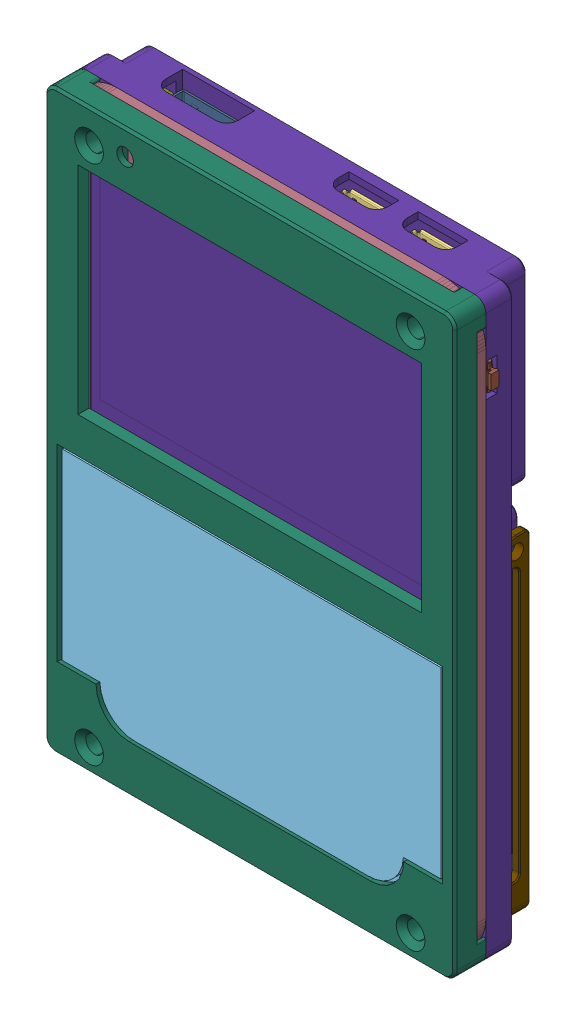
SolidWorks assembly beepy-v1, configuration 默认. Lengths in mm.
Overall size (74.67 104 15.57).
374 component instances, 56 part files, 23 mates.
Components (placement in the parent):
- Raspberry Pi Zero 2 W-1: Raspberry Pi Zero 2 W [默认] at (-86.2469 93.6162 0.7033) x (1 0 0) z (0 1 0) size (65.8 5.05 30.58)
  - PCB, Raspberry Pi Zero 2 W-1: PCB, Raspberry Pi Zero 2 W [默认] at origin size (65 1.6 30)
  - RP3A0-AU 2105 201221C, Raspberry Pi Zero 2 W-1: RP3A0-AU 2105 201221C, Raspberry Pi Zero 2 W [默认] at (-5.5 0.8 1) size (15 1 15)
  - MicroUSB Port, Raspberry Pi Zero 2 W-1: MicroUSB Port, Raspberry Pi Zero 2 W [默认] at (8.9 0.8 13) size (7.99 2.94 5.43)
  - SD Card Slot, Raspberry Pi Zero 2 W-1: SD Card Slot, Raspberry Pi Zero 2 W [默认] at (-25.5 0.8 -2) x (0 0 1) z (-1 0 0) size (11.95 1.45 11.4)
  - Wireless Module Cover, Raspberry Pi Zero 2 W-1: Wireless Module Cover, Raspberry Pi Zero 2 W [默认] at (11 0.8 1.5) size (12.6 1.6 12.6)
  - Crystal Resonator, Raspberry Pi Zero 2 W-1: Crystal Resonator, Raspberry Pi Zero 2 W [默认] at (-17.5 0.8 -1.5) size (2.2 0.6 3.2)
  - LED, Raspberry Pi Zero 2 W-1: LED, Raspberry Pi Zero 2 W [默认] at (27.5 0.8 7.8) size (1.2 0.4 0.8)
  - Diode, Schottky, Raspberry Pi Zero 2 W-1: Diode, Schottky, Raspberry Pi Zero 2 W [默认] at (-11 0.8 12) size (1.8 1 3.7)
  - 54548-2271, 22 Pin FPC Connector, Raspberry Pi Zero 2 W-1: 54548-2271, 22 Pin FPC Connector, Raspberry Pi Zero 2 W [默认] at (28.75 0.82 0) x (0 0 -1) z (1 0 0) size (16.2 1.2 5)
  - Mini HDMI Receptacle Port, Raspberry Pi Zero 2 W-1: Mini HDMI Receptacle Port, Raspberry Pi Zero 2 W [默认] at (-20.1 2.65 15) size (12.9 4.05 7.7)
  - PAM2306AYPKE, Switching Voltage Regulators Dual PWM Step-Down 40uA 1A_ 1.5MHz, Raspberry Pi Zero 2 W-1: PAM2306AYPKE, Switching Voltage Regulators Dual PWM Step-Down 40uA 1A_ 1.5MHz, Raspberry Pi Zero 2 W [默认] at (23 0.8 1) x (0 0 1) z (-1 0 0) size (3.4 1 3)
  - RT9081A-1BGQZA, Fixed LDO Voltage Regulator, 0.8V-5.5Vin, 140mV drop,_ 1.25Vout, 0.5Aout, Raspberry Pi Zero 2 W_default-1: RT9081A-1BGQZA, Fixed LDO Voltage Regulator, 0.8V-5.5Vin, 140mV drop,_ 1.25Vout, 0.5Aout, Raspberry Pi Zero 2 W_default [默认] at (14.8 0.8 -7.2) size (1.2 0.1 1.2)
  - RT8088AWSC, IC Reg Buck Prog 3A Sync 15WLCSP, Raspberry Pi Zero 2 W_d_efault-1: RT8088AWSC, IC Reg Buck Prog 3A Sync 15WLCSP, Raspberry Pi Zero 2 W_d_efault [默认] at (20 0.8 -3.6) size (1.36 0.4 2.16)
  - SMD Inductor, Configurable, Raspberry Pi Zero 2 W_L1-1: SMD Inductor, Configurable, Raspberry Pi Zero 2 W_L1 [默认] at (20.5 0.8 7.5) size (4 1.8 4)
  - SMD Inductor, Configurable, Raspberry Pi Zero 2 W_L2-1: SMD Inductor, Configurable, Raspberry Pi Zero 2 W_L2 [默认] at (24.5 0.8 -2) size (2.5 1.2 2)
  - SMD Capacitor, Configurable, Raspberry Pi Zero 2 W_C1-1: SMD Capacitor, Configurable, Raspberry Pi Zero 2 W_C1 [默认] at (24.9 0.8 7.7) size (1.2 0.45 2)
  - MicroUSB Port, Raspberry Pi Zero 2 W-2: MicroUSB Port, Raspberry Pi Zero 2 W [默认] at (21.5 0.8 13) size (7.99 2.94 5.43)
  - SMD Capacitor, Configurable, Raspberry Pi Zero 2 W_C3-1: SMD Capacitor, Configurable, Raspberry Pi Zero 2 W_C3 [默认] at (20.5 0.8 3) size (0.85 0.45 1.55)
  - SMD Capacitor, Configurable, Raspberry Pi Zero 2 W_C3-2: SMD Capacitor, Configurable, Raspberry Pi Zero 2 W_C3 [默认] at (18.7 0.8 3) size (0.85 0.45 1.55)
  - SMD Capacitor, Configurable, Raspberry Pi Zero 2 W_C1-2: SMD Capacitor, Configurable, Raspberry Pi Zero 2 W_C1 [默认] at (27.3 0.8 2.2) size (1.2 0.45 2)
  - SMD Capacitor, Configurable, Raspberry Pi Zero 2 W_C3-3: SMD Capacitor, Configurable, Raspberry Pi Zero 2 W_C3 [默认] at (25.7 0.8 2.2) size (0.85 0.45 1.55)
  - SMD Capacitor, Configurable, Raspberry Pi Zero 2 W_C1-3: SMD Capacitor, Configurable, Raspberry Pi Zero 2 W_C1 [默认] at (22.8 0.8 -5.1) x (0 0 -1) z (1 0 0) size (1.2 0.45 2)
  - SMD Capacitor, Configurable, Raspberry Pi Zero 2 W_C3-4: SMD Capacitor, Configurable, Raspberry Pi Zero 2 W_C3 [默认] at (20 0.8 -6.4) x (0 0 -1) z (1 0 0) size (0.85 0.45 1.55)
  - SMD Capacitor, Configurable, Raspberry Pi Zero 2 W_C3-5: SMD Capacitor, Configurable, Raspberry Pi Zero 2 W_C3 [默认] at (15.8 0.8 -6.1) x (0 0 -1) z (1 0 0) size (0.85 0.45 1.55)
  - SMD Capacitor, Configurable, Raspberry Pi Zero 2 W_C3-6: SMD Capacitor, Configurable, Raspberry Pi Zero 2 W_C3 [默认] at (13 0.8 -6.1) x (0 0 -1) z (1 0 0) size (0.85 0.45 1.55)
  - SMD Capacitor, Configurable, Raspberry Pi Zero 2 W_C3-7: SMD Capacitor, Configurable, Raspberry Pi Zero 2 W_C3 [默认] at (14.8 0.8 12.5) size (0.85 0.45 1.55)
  - SMD Capacitor, Configurable, Raspberry Pi Zero 2 W_C2-1: SMD Capacitor, Configurable, Raspberry Pi Zero 2 W_C2 [默认] at (-9.5 0.8 10.4) size (0.3 0.25 0.6)
  - SMD Capacitor, Configurable, Raspberry Pi Zero 2 W_C10-1: SMD Capacitor, Configurable, Raspberry Pi Zero 2 W_C10 [默认] at (-31.4 0.8 6) size (0.5 0.35 1)
  - SMD Capacitor, Configurable, Raspberry Pi Zero 2 W_C10-2: SMD Capacitor, Configurable, Raspberry Pi Zero 2 W_C10 [默认] at (-6.1 0.8 13.7) x (0 0 -1) z (1 0 0) size (0.5 0.35 1)
  - SMD Capacitor, Configurable, Raspberry Pi Zero 2 W_C10-3: SMD Capacitor, Configurable, Raspberry Pi Zero 2 W_C10 [默认] at (-2.9 0.8 13.7) x (0 0 -1) z (1 0 0) size (0.5 0.35 1)
  - SMD Capacitor, Configurable, Raspberry Pi Zero 2 W_C10-4: SMD Capacitor, Configurable, Raspberry Pi Zero 2 W_C10 [默认] at (-6.1 0.8 11.9) x (0 0 -1) z (1 0 0) size (0.5 0.35 1)
  - SMD Capacitor, Configurable, Raspberry Pi Zero 2 W_C10-5: SMD Capacitor, Configurable, Raspberry Pi Zero 2 W_C10 [默认] at (-2.9 0.8 11.9) x (0 0 -1) z (1 0 0) size (0.5 0.35 1)
  - SMD Capacitor, Configurable, Raspberry Pi Zero 2 W_C10-6: SMD Capacitor, Configurable, Raspberry Pi Zero 2 W_C10 [默认] at (-4.6 0.8 9.5) x (0 0 -1) z (1 0 0) size (0.5 0.35 1)
  - SMD Capacitor, Configurable, Raspberry Pi Zero 2 W_C10-7: SMD Capacitor, Configurable, Raspberry Pi Zero 2 W_C10 [默认] at (-7.3 0.8 8.9) x (0 0 -1) z (1 0 0) size (0.5 0.35 1)
  - SMD Capacitor, Configurable, Raspberry Pi Zero 2 W_C2-2: SMD Capacitor, Configurable, Raspberry Pi Zero 2 W_C2 [默认] at (-4.6 0.8 8.8) x (0 0 -1) z (1 0 0) size (0.3 0.25 0.6)
  - SMD Capacitor, Configurable, Raspberry Pi Zero 2 W_C10-8: SMD Capacitor, Configurable, Raspberry Pi Zero 2 W_C10 [默认] at (2.9 0.8 -1.5) x (-1 0 0) z (0 0 -1) size (0.5 0.35 1)
  - SMD Capacitor, Configurable, Raspberry Pi Zero 2 W_C10-9: SMD Capacitor, Configurable, Raspberry Pi Zero 2 W_C10 [默认] at (3.1 0.8 0.3) x (0 0 -1) z (1 0 0) size (0.5 0.35 1)
  - SMD Capacitor, Configurable, Raspberry Pi Zero 2 W_C2-3: SMD Capacitor, Configurable, Raspberry Pi Zero 2 W_C2 [默认] at (-2.4 0.8 8.8) x (0 0 -1) z (1 0 0) size (0.3 0.25 0.6)
  - SMD Capacitor, Configurable, Raspberry Pi Zero 2 W_C2-4: SMD Capacitor, Configurable, Raspberry Pi Zero 2 W_C2 [默认] at (-9.7 0.8 8.8) x (0 0 -1) z (1 0 0) size (0.3 0.25 0.6)
  - SMD Capacitor, Configurable, Raspberry Pi Zero 2 W_C2-5: SMD Capacitor, Configurable, Raspberry Pi Zero 2 W_C2 [默认] at (-8.5 0.8 9.2) x (-1 0 0) z (0 0 -1) size (0.3 0.25 0.6)
  - SMD Capacitor, Configurable, Raspberry Pi Zero 2 W_C2-6: SMD Capacitor, Configurable, Raspberry Pi Zero 2 W_C2 [默认] at (3.1 0.8 2.2) x (-1 0 0) z (0 0 -1) size (0.3 0.25 0.6)
  - SMD Capacitor, Configurable, Raspberry Pi Zero 2 W_C2-7: SMD Capacitor, Configurable, Raspberry Pi Zero 2 W_C2 [默认] at (3 0.8 3.7) x (-1 0 0) z (0 0 -1) size (0.3 0.25 0.6)
  - SMD Capacitor, Configurable, Raspberry Pi Zero 2 W_C2-8: SMD Capacitor, Configurable, Raspberry Pi Zero 2 W_C2 [默认] at (3 0.8 5.5) x (-1 0 0) z (0 0 -1) size (0.3 0.25 0.6)
  - SMD Capacitor, Configurable, Raspberry Pi Zero 2 W_C10-10: SMD Capacitor, Configurable, Raspberry Pi Zero 2 W_C10 [默认] at (-27.8 0.8 7.8) x (0 0 -1) z (1 0 0) size (0.5 0.35 1)
  - SMD Capacitor, Configurable, Raspberry Pi Zero 2 W_C2-9: SMD Capacitor, Configurable, Raspberry Pi Zero 2 W_C2 [默认] at (-12.7 0.8 13.7) x (0 0 -1) z (1 0 0) size (0.3 0.25 0.6)
  - SMD Capacitor, Configurable, Raspberry Pi Zero 2 W_C10-11: SMD Capacitor, Configurable, Raspberry Pi Zero 2 W_C10 [默认] at (-17.7 0.8 -3.8) x (0 0 -1) z (1 0 0) size (0.5 0.35 1)
  - SMD Capacitor, Configurable, Raspberry Pi Zero 2 W_C10-12: SMD Capacitor, Configurable, Raspberry Pi Zero 2 W_C10 [默认] at (-17.5 0.8 1) x (0 0 -1) z (1 0 0) size (0.5 0.35 1)
  - SMD Capacitor, Configurable, Raspberry Pi Zero 2 W_C2-10: SMD Capacitor, Configurable, Raspberry Pi Zero 2 W_C2 [默认] at (-7.7 0.8 -7.4) x (0 0 -1) z (1 0 0) size (0.3 0.25 0.6)
  - SMD Capacitor, Configurable, Raspberry Pi Zero 2 W_C2-11: SMD Capacitor, Configurable, Raspberry Pi Zero 2 W_C2 [默认] at (-5.4 0.8 -7.5) x (-1 0 0) z (0 0 -1) size (0.3 0.25 0.6)
  - SMD Capacitor, Configurable, Raspberry Pi Zero 2 W_C2-12: SMD Capacitor, Configurable, Raspberry Pi Zero 2 W_C2 [默认] at (-0.15 0.8 9) x (-1 0 0) z (0 0 -1) size (0.3 0.25 0.6)
  - SMD Capacitor, Configurable, Raspberry Pi Zero 2 W_C2-13: SMD Capacitor, Configurable, Raspberry Pi Zero 2 W_C2 [默认] at (-1.3 0.8 8.8) x (0 0 -1) z (1 0 0) size (0.3 0.25 0.6)
  - SMD Capacitor, Configurable, Raspberry Pi Zero 2 W_C10-13: SMD Capacitor, Configurable, Raspberry Pi Zero 2 W_C10 [默认] at (-15 0.8 6.4) x (0 0 -1) z (1 0 0) size (0.5 0.35 1)
  - SMD Capacitor, Configurable, Raspberry Pi Zero 2 W_C2-14: SMD Capacitor, Configurable, Raspberry Pi Zero 2 W_C2 [默认] at (-14.2 0.8 -2.1) x (0 0 -1) z (1 0 0) size (0.3 0.25 0.6)
  - SMD Capacitor, Configurable, Raspberry Pi Zero 2 W_C10-14: SMD Capacitor, Configurable, Raspberry Pi Zero 2 W_C10 [默认] at (-15 0.8 -1) size (0.5 0.35 1)
  - SMD Capacitor, Configurable, Raspberry Pi Zero 2 W_C10-15: SMD Capacitor, Configurable, Raspberry Pi Zero 2 W_C10 [默认] at (-14.9 0.8 1.1) size (0.5 0.35 1)
  - SMD Capacitor, Configurable, Raspberry Pi Zero 2 W_C2-15: SMD Capacitor, Configurable, Raspberry Pi Zero 2 W_C2 [默认] at (-14.3 0.8 -7.2) x (0 0 -1) z (1 0 0) size (0.3 0.25 0.6)
  - SMD Capacitor, Configurable, Raspberry Pi Zero 2 W_C2-16: SMD Capacitor, Configurable, Raspberry Pi Zero 2 W_C2 [默认] at (-14.1 0.8 -6) x (0 0 -1) z (1 0 0) size (0.3 0.25 0.6)
  - SMD Capacitor, Configurable, Raspberry Pi Zero 2 W_C2-17: SMD Capacitor, Configurable, Raspberry Pi Zero 2 W_C2 [默认] at (-13.3 0.8 1.7) size (0.3 0.25 0.6)
  - SMD Capacitor, Configurable, Raspberry Pi Zero 2 W_C2-18: SMD Capacitor, Configurable, Raspberry Pi Zero 2 W_C2 [默认] at (-13.3 0.8 -0.9) size (0.3 0.25 0.6)
  - SMD Capacitor, Configurable, Raspberry Pi Zero 2 W_C2-19: SMD Capacitor, Configurable, Raspberry Pi Zero 2 W_C2 [默认] at (-14.2 0.8 -2.7) x (0 0 -1) z (1 0 0) size (0.3 0.25 0.6)
  - SMD Capacitor, Configurable, Raspberry Pi Zero 2 W_C2-20: SMD Capacitor, Configurable, Raspberry Pi Zero 2 W_C2 [默认] at (-14.2 0.8 -3.3) x (0 0 -1) z (1 0 0) size (0.3 0.25 0.6)
  - SMD Capacitor, Configurable, Raspberry Pi Zero 2 W_C2-21: SMD Capacitor, Configurable, Raspberry Pi Zero 2 W_C2 [默认] at (-14.2 0.8 -3.9) x (0 0 -1) z (1 0 0) size (0.3 0.25 0.6)
  - SMD Capacitor, Configurable, Raspberry Pi Zero 2 W_C2-22: SMD Capacitor, Configurable, Raspberry Pi Zero 2 W_C2 [默认] at (-14.1 0.8 3.7) x (0 0 -1) z (1 0 0) size (0.3 0.25 0.6)
  - SMD Capacitor, Configurable, Raspberry Pi Zero 2 W_C2-23: SMD Capacitor, Configurable, Raspberry Pi Zero 2 W_C2 [默认] at (-15 0.8 3) size (0.3 0.25 0.6)
  - SMD Capacitor, Configurable, Raspberry Pi Zero 2 W_C2-24: SMD Capacitor, Configurable, Raspberry Pi Zero 2 W_C2 [默认] at (-15.8 0.8 3) size (0.3 0.25 0.6)
  - SMD Capacitor, Configurable, Raspberry Pi Zero 2 W_C2-25: SMD Capacitor, Configurable, Raspberry Pi Zero 2 W_C2 [默认] at (25.8 0.8 -5.6) x (0 0 -1) z (1 0 0) size (0.3 0.25 0.6)
  - SMD Capacitor, Configurable, Raspberry Pi Zero 2 W_C2-26: SMD Capacitor, Configurable, Raspberry Pi Zero 2 W_C2 [默认] at (25.1 0.8 -6.5) size (0.3 0.25 0.6)
  - SMD Capacitor, Configurable, Raspberry Pi Zero 2 W_C2-27: SMD Capacitor, Configurable, Raspberry Pi Zero 2 W_C2 [默认] at (25.3 0.8 4.9) x (0 0 -1) z (1 0 0) size (0.3 0.25 0.6)
  - SMD Capacitor, Configurable, Raspberry Pi Zero 2 W_C2-28: SMD Capacitor, Configurable, Raspberry Pi Zero 2 W_C2 [默认] at (18.7 0.8 -3) size (0.3 0.25 0.6)
  - SMD Capacitor, Configurable, Raspberry Pi Zero 2 W_C2-29: SMD Capacitor, Configurable, Raspberry Pi Zero 2 W_C2 [默认] at (6.9269 0.8 8.9) x (0 0 -1) z (1 0 0) size (0.3 0.25 0.6)
  - SMD Capacitor, Configurable, Raspberry Pi Zero 2 W_C2-30: SMD Capacitor, Configurable, Raspberry Pi Zero 2 W_C2 [默认] at (3.5 0.8 -1.5) x (-1 0 0) z (0 0 -1) size (0.3 0.25 0.6)
  - SMD Resistor, Configurable, Raspberry Pi Zero 2 W_R1-1: SMD Resistor, Configurable, Raspberry Pi Zero 2 W_R1 [默认] at (-18.4 0.8 -8.2) size (0.5 0.35 1)
  - SMD Resistor, Configurable, Raspberry Pi Zero 2 W_R1-2: SMD Resistor, Configurable, Raspberry Pi Zero 2 W_R1 [默认] at (-17.1 0.8 -8.2) size (0.5 0.35 1)
  - SMD Resistor, Configurable, Raspberry Pi Zero 2 W_R1-3: SMD Resistor, Configurable, Raspberry Pi Zero 2 W_R1 [默认] at (23.9 0.8 -8) size (0.5 0.35 1)
  - SMD Resistor, Configurable, Raspberry Pi Zero 2 W_R12-1: SMD Resistor, Configurable, Raspberry Pi Zero 2 W_R12 [默认] at (24.9 0.8 -8) size (0.3 0.23 0.6)
  - SMD Resistor, Configurable, Raspberry Pi Zero 2 W_R1-4: SMD Resistor, Configurable, Raspberry Pi Zero 2 W_R1 [默认] at (-10.8 0.8 -7.3) x (0 0 1) z (-1 0 0) size (0.5 0.35 1)
  - SMD Resistor, Configurable, Raspberry Pi Zero 2 W_R1-5: SMD Resistor, Configurable, Raspberry Pi Zero 2 W_R1 [默认] at (-14.3 0.8 -4.7) x (0 0 1) z (-1 0 0) size (0.5 0.35 1)
  - SMD Resistor, Configurable, Raspberry Pi Zero 2 W_R1-6: SMD Resistor, Configurable, Raspberry Pi Zero 2 W_R1 [默认] at (-13.3 0.8 -7.3) x (0 0 1) z (-1 0 0) size (0.5 0.35 1)
  - SMD Resistor, Configurable, Raspberry Pi Zero 2 W_R1-7: SMD Resistor, Configurable, Raspberry Pi Zero 2 W_R1 [默认] at (-17.7 0.8 -5.8) x (0 0 1) z (-1 0 0) size (0.5 0.35 1)
  - SMD Resistor, Configurable, Raspberry Pi Zero 2 W_R1-8: SMD Resistor, Configurable, Raspberry Pi Zero 2 W_R1 [默认] at (-17.7 0.8 -4.8) x (0 0 1) z (-1 0 0) size (0.5 0.35 1)
  - SMD Resistor, Configurable, Raspberry Pi Zero 2 W_R1-9: SMD Resistor, Configurable, Raspberry Pi Zero 2 W_R1 [默认] at (-27.7 0.8 4.8) x (0 0 1) z (-1 0 0) size (0.5 0.35 1)
  - SMD Resistor, Configurable, Raspberry Pi Zero 2 W_R1-10: SMD Resistor, Configurable, Raspberry Pi Zero 2 W_R1 [默认] at (-15 0.8 5.4) x (0 0 1) z (-1 0 0) size (0.5 0.35 1)
  - SMD Resistor, Configurable, Raspberry Pi Zero 2 W_R1-11: SMD Resistor, Configurable, Raspberry Pi Zero 2 W_R1 [默认] at (-6.7 0.8 9.6958) x (0 0 1) z (-1 0 0) size (0.5 0.35 1)
  - SMD Resistor, Configurable, Raspberry Pi Zero 2 W_R1-12: SMD Resistor, Configurable, Raspberry Pi Zero 2 W_R1 [默认] at (-11.7 0.8 8.9) x (0 0 1) z (-1 0 0) size (0.5 0.35 1)
  - SMD Resistor, Configurable, Raspberry Pi Zero 2 W_R1-13: SMD Resistor, Configurable, Raspberry Pi Zero 2 W_R1 [默认] at (24.8 0.8 5.7) x (0 0 1) z (-1 0 0) size (0.5 0.35 1)
  - SMD Resistor, Configurable, Raspberry Pi Zero 2 W_R1-14: SMD Resistor, Configurable, Raspberry Pi Zero 2 W_R1 [默认] at (27.2 0.8 4.3) x (0 0 1) z (-1 0 0) size (0.5 0.35 1)
  - SMD Resistor, Configurable, Raspberry Pi Zero 2 W_R1-15: SMD Resistor, Configurable, Raspberry Pi Zero 2 W_R1 [默认] at (27.2 0.8 5.3) x (0 0 1) z (-1 0 0) size (0.5 0.35 1)
  - SMD Resistor, Configurable, Raspberry Pi Zero 2 W_R1-16: SMD Resistor, Configurable, Raspberry Pi Zero 2 W_R1 [默认] at (27.2 0.8 6.4) x (0 0 1) z (-1 0 0) size (0.5 0.35 1)
  - SMD Resistor, Configurable, Raspberry Pi Zero 2 W_R1-17: SMD Resistor, Configurable, Raspberry Pi Zero 2 W_R1 [默认] at (26.5 0.8 -6.5) x (0 0 1) z (-1 0 0) size (0.5 0.35 1)
  - SMD Resistor, Configurable, Raspberry Pi Zero 2 W_R1-18: SMD Resistor, Configurable, Raspberry Pi Zero 2 W_R1 [默认] at (26.5 0.8 -7.4) x (0 0 1) z (-1 0 0) size (0.5 0.35 1)
  - SMD Resistor, Configurable, Raspberry Pi Zero 2 W_R1-19: SMD Resistor, Configurable, Raspberry Pi Zero 2 W_R1 [默认] at (26.5 0.8 -8.6) x (0 0 1) z (-1 0 0) size (0.5 0.35 1)
  - SMD Resistor, Configurable, Raspberry Pi Zero 2 W_R1-20: SMD Resistor, Configurable, Raspberry Pi Zero 2 W_R1 [默认] at (3.5 0.8 -6.6) x (0.707107 0 0.707107) z (-0.707107 0 0.707107) size (0.5 0.35 1)
  - SMD Capacitor, Configurable, Raspberry Pi Zero 2 W_C2-31: SMD Capacitor, Configurable, Raspberry Pi Zero 2 W_C2 [默认] at (14.6 0.8 -8.3) x (0 0 -1) z (1 0 0) size (0.3 0.25 0.6)
- beeperv2-1: beeperv2 [默认] at (-49.2569 6.9162 4.5433) size (74.67 104 10.1)
  - RGB LED SMD 2121 v1-1: RGB LED SMD 2121 v1 [默认] at (-59.47 99.29 1.62) size (2.1 2.1 1)
    - COMPOUND-1: COMPOUND [默认] at origin size (2.1 2.1 1)
  - R_0603_1608Metric-1: R_0603_1608Metric [默认] at (-46.22 67.4075 -0.05) x (-1 0 0) z (0 0 -1) size (1.6 0.8 0.45)
    - SOLID-1: SOLID [默认] at origin size (1.6 0.8 0.45)
  - s7141-45-1: s7141-45 [默认] at (-20.4916 74.98 -0.05) x (1 0 0) z (0 1 0) size (2.3 2.57 4.6)
    - COMPOUND (1)-1: COMPOUND (1) [默认] at origin size (2.3 2.57 4.6)
  - s7141-45-2: s7141-45 [默认] at (-28.1032 75.42 -0.05) x (-1 0 0) z (0 -1 0) size (2.3 2.57 4.6)
    - COMPOUND (1)-1: COMPOUND (1) [默认] at origin size (2.3 2.57 4.6)
  - s7141-45-3: s7141-45 [默认] at (-25.5726 74.98 -0.05) x (1 0 0) z (0 1 0) size (2.3 2.57 4.6)
    - COMPOUND (1)-1: COMPOUND (1) [默认] at origin size (2.3 2.57 4.6)
  - SSOP-8_5.25x5.24mm_P1.27mm-1: SSOP-8_5.25x5.24mm_P1.27mm [默认] at (-21.02 19.19 -0.05) x (1 0 0) z (0 0 -1) size (8.22 5.24 1.6)
    - SOLID (1)-1: SOLID (1) [默认] at origin size (8.22 5.24 1.6)
  - s7141-45-4: s7141-45 [默认] at (-53.5184 74.98 -0.05) x (1 0 0) z (0 1 0) size (2.3 2.57 4.6)
    - COMPOUND (1)-1: COMPOUND (1) [默认] at origin size (2.3 2.57 4.6)
  - R_0603_1608Metric-2: R_0603_1608Metric [默认] at (-15.62 33.785 -0.05) x (0 1 0) z (0 0 -1) size (1.6 0.8 0.45)
    - SOLID-1: SOLID [默认] at origin size (1.6 0.8 0.45)
  - SSOP-16_4.4x5.2mm_P0.65mm-1: SSOP-16_4.4x5.2mm_P0.65mm [默认] at (-56.8325 11.275 -0.05) x (-1 0 0) z (0 0 -1) size (6.5 5.2 1.4)
    - SOLID (2)-1: SOLID (2) [默认] at origin size (6.5 5.2 1.4)
  - SOT-23-1: SOT-23 [默认] at (-21.45 37.19 -0.05) x (0 -1 0) z (0 0 -1) size (2.5 3 1.2)
    - SOLID (3)-1: SOLID (3) [默认] at origin size (2.5 3 1.2)
  - SOT-23-5-1: SOT-23-5 [默认] at (-18.37 44.26 -0.05) x (0 1 0) z (0 0 -1) size (2.8 2.9 1.55)
    - SOLID (4)-1: SOLID (4) [默认] at origin size (2.8 2.9 1.55)
  - EVQPU-LC-02K-1: EVQPU-LC-02K [默认] at (-2.08 91.37 -0.05) x (0 -1 0) z (1 0 0) size (6.4 2.15 4.54)
    - SOLID (5)-1: SOLID (5) [默认] at origin size (6.4 2.15 4.54)
  - R_0603_1608Metric-3: R_0603_1608Metric [默认] at (-18.25 54.395 -0.05) x (0 1 0) z (0 0 -1) size (1.6 0.8 0.45)
    - SOLID-1: SOLID [默认] at origin size (1.6 0.8 0.45)
  - SOT-23-2: SOT-23 [默认] at (-10.48 51 -0.05) x (0 -1 0) z (0 0 -1) size (2.5 3 1.2)
    - SOLID (3)-1: SOLID (3) [默认] at origin size (2.5 3 1.2)
  - s7141-45-5: s7141-45 [默认] at (-38.2653 75.42 -0.05) x (-1 0 0) z (0 -1 0) size (2.3 2.57 4.6)
    - COMPOUND (1)-1: COMPOUND (1) [默认] at origin size (2.3 2.57 4.6)
  - SOT-23-5-2: SOT-23-5 [默认] at (-21.77 44.26 -0.05) x (0 1 0) z (0 0 -1) size (2.8 2.9 1.55)
    - SOLID (4)-1: SOLID (4) [默认] at origin size (2.8 2.9 1.55)
  - s7141-45-6: s7141-45 [默认] at (-15.4105 74.98 -0.05) x (1 0 0) z (0 1 0) size (2.3 2.57 4.6)
    - COMPOUND (1)-1: COMPOUND (1) [默认] at origin size (2.3 2.57 4.6)
  - s7141-45-7: s7141-45 [默认] at (-17.9411 75.42 -0.05) x (-1 0 0) z (0 -1 0) size (2.3 2.57 4.6)
    - COMPOUND (1)-1: COMPOUND (1) [默认] at origin size (2.3 2.57 4.6)
  - C_0603_1608Metric-1: C_0603_1608Metric [默认] at (-14.3 20.58 -0.05) x (0 -1 0) z (0 0 -1) size (1.6 0.8 0.8)
    - SOLID (6)-1: SOLID (6) [默认] at origin size (1.6 0.8 0.8)
  - C_1206_3216Metric-1: C_1206_3216Metric [默认] at (-63.04 13.75 -0.05) x (-1 0 0) z (0 0 -1) size (3.2 1.6 1.6)
    - SOLID (7)-1: SOLID (7) [默认] at origin size (3.2 1.6 1.6)
  - C_0603_1608Metric-2: C_0603_1608Metric [默认] at (-7.93 23.79 -0.05) x (1 0 0) z (0 0 -1) size (1.6 0.8 0.8)
    - SOLID (6)-1: SOLID (6) [默认] at origin size (1.6 0.8 0.8)
  - SOT-23-3: SOT-23 [默认] at (-17.28 50.995 -0.05) x (0 -1 0) z (0 0 -1) size (2.5 3 1.2)
    - SOLID (3)-1: SOLID (3) [默认] at origin size (2.5 3 1.2)
  - s7141-45-8: s7141-45 [默认] at (-58.5895 75.42 -0.05) x (-1 0 0) z (0 -1 0) size (2.3 2.57 4.6)
    - COMPOUND (1)-1: COMPOUND (1) [默认] at origin size (2.3 2.57 4.6)
  - C_0603_1608Metric-3: C_0603_1608Metric [默认] at (-18.15 47.04 -0.05) x (-1 0 0) z (0 0 -1) size (1.6 0.8 0.8)
    - SOLID (6)-1: SOLID (6) [默认] at origin size (1.6 0.8 0.8)
  - R_0603_1608Metric-4: R_0603_1608Metric [默认] at (-51.45 9.06 -0.05) x (-1 0 0) z (0 0 -1) size (1.6 0.8 0.45)
    - SOLID-1: SOLID [默认] at origin size (1.6 0.8 0.45)
  - L_TDK_SLF7032-1: L_TDK_SLF7032 [默认] at (-49.3325 16.305 -0.05) x (-1 0 0) z (0 0 -1) size (7 7 2.5)
    - SOLID (8)-1: SOLID (8) [默认] at origin size (7 7 2.5)
  - R_0603_1608Metric-5: R_0603_1608Metric [默认] at (-62.215 10.41 -0.05) x (-1 0 0) z (0 0 -1) size (1.6 0.8 0.45)
    - SOLID-1: SOLID [默认] at origin size (1.6 0.8 0.45)
  - R_0603_1608Metric-6: R_0603_1608Metric [默认] at (-37.38 11.04 -0.05) x (1 0 0) z (0 0 -1) size (1.6 0.8 0.45)
    - SOLID-1: SOLID [默认] at origin size (1.6 0.8 0.45)
  - C_0603_1608Metric-4: C_0603_1608Metric [默认] at (-52.2025 11.275 -0.05) x (0 1 0) z (0 0 -1) size (1.6 0.8 0.8)
    - SOLID (6)-1: SOLID (6) [默认] at origin size (1.6 0.8 0.8)
  - R_0603_1608Metric-7: R_0603_1608Metric [默认] at (-16.31 54.395 -0.05) x (0 1 0) z (0 0 -1) size (1.6 0.8 0.45)
    - SOLID-1: SOLID [默认] at origin size (1.6 0.8 0.45)
  - s7141-45-9: s7141-45 [默认] at (-38.2753 74.98 -0.05) x (1 0 0) z (0 1 0) size (2.3 2.57 4.6)
    - COMPOUND (1)-1: COMPOUND (1) [默认] at origin size (2.3 2.57 4.6)
  - C_0603_1608Metric-5: C_0603_1608Metric [默认] at (-21.13 28.18 -0.05) x (-1 0 0) z (0 0 -1) size (1.6 0.8 0.8)
    - SOLID (6)-1: SOLID (6) [默认] at origin size (1.6 0.8 0.8)
  - s7141-45-10: s7141-45 [默认] at (-35.7247 75.42 -0.05) x (-1 0 0) z (0 -1 0) size (2.3 2.57 4.6)
    - COMPOUND (1)-1: COMPOUND (1) [默认] at origin size (2.3 2.57 4.6)
  - s7141-45-11: s7141-45 [默认] at (-28.1132 74.98 -0.05) x (1 0 0) z (0 1 0) size (2.3 2.57 4.6)
    - COMPOUND (1)-1: COMPOUND (1) [默认] at origin size (2.3 2.57 4.6)
  - R_0603_1608Metric-8: R_0603_1608Metric [默认] at (-8.05 54.4 -0.05) x (0 1 0) z (0 0 -1) size (1.6 0.8 0.45)
    - SOLID-1: SOLID [默认] at origin size (1.6 0.8 0.45)
  - C_0603_1608Metric-6: C_0603_1608Metric [默认] at (-63.86 20.5 -0.05) x (-1 0 0) z (0 0 -1) size (1.6 0.8 0.8)
    - SOLID (6)-1: SOLID (6) [默认] at origin size (1.6 0.8 0.8)
  - R_0603_1608Metric-9: R_0603_1608Metric [默认] at (-51.45 7.6 -0.05) x (1 0 0) z (0 0 -1) size (1.6 0.8 0.45)
    - SOLID-1: SOLID [默认] at origin size (1.6 0.8 0.45)
  - R_0603_1608Metric-10: R_0603_1608Metric [默认] at (-14.85 54.4 -0.05) x (0 1 0) z (0 0 -1) size (1.6 0.8 0.45)
    - SOLID-1: SOLID [默认] at origin size (1.6 0.8 0.45)
  - QFN-56-1EP_7x7mm_P0.4mm_EP5.6x5.6mm-1: QFN-56-1EP_7x7mm_P0.4mm_EP5.6x5.6mm [默认] at (-14.53 27.18 -0.05) x (1 0 0) z (0 0 -1) size (7 7 0.92)
    - SOLID (9)-1: SOLID (9) [默认] at origin size (7 7 0.92)
  - R_0603_1608Metric-11: R_0603_1608Metric [默认] at (-26.97 20.76 -0.05) x (0 -1 0) z (0 0 -1) size (1.6 0.8 0.45)
    - SOLID-1: SOLID [默认] at origin size (1.6 0.8 0.45)
  - C_0603_1608Metric-7: C_0603_1608Metric [默认] at (-50.7425 11.275 -0.05) x (0 1 0) z (0 0 -1) size (1.6 0.8 0.8)
    - SOLID (6)-1: SOLID (6) [默认] at origin size (1.6 0.8 0.8)
  - R_0603_1608Metric-12: R_0603_1608Metric [默认] at (-21.65 54.395 -0.05) x (0 1 0) z (0 0 -1) size (1.6 0.8 0.45)
    - SOLID-1: SOLID [默认] at origin size (1.6 0.8 0.45)
  - s7141-45-12: s7141-45 [默认] at (-40.8158 74.98 -0.05) x (1 0 0) z (0 1 0) size (2.3 2.57 4.6)
    - COMPOUND (1)-1: COMPOUND (1) [默认] at origin size (2.3 2.57 4.6)
  - C_0603_1608Metric-8: C_0603_1608Metric [默认] at (-38.56 66.22 -0.05) x (0 1 0) z (0 0 -1) size (1.6 0.8 0.8)
    - SOLID (6)-1: SOLID (6) [默认] at origin size (1.6 0.8 0.8)
  - R_0603_1608Metric-13: R_0603_1608Metric [默认] at (-29.7011 8.584 -0.05) x (1 0 0) z (0 0 -1) size (1.6 0.8 0.45)
    - SOLID-1: SOLID [默认] at origin size (1.6 0.8 0.45)
  - C_0603_1608Metric-9: C_0603_1608Metric [默认] at (-14.16 33.785 -0.05) x (0 1 0) z (0 0 -1) size (1.6 0.8 0.8)
    - SOLID (6)-1: SOLID (6) [默认] at origin size (1.6 0.8 0.8)
  - s7141-45-13: s7141-45 [默认] at (-17.9511 74.98 -0.05) x (1 0 0) z (0 1 0) size (2.3 2.57 4.6)
    - COMPOUND (1)-1: COMPOUND (1) [默认] at origin size (2.3 2.57 4.6)
  - R_0603_1608Metric-14: R_0603_1608Metric [默认] at (-7.93 25.25 -0.05) x (-1 0 0) z (0 0 -1) size (1.6 0.8 0.45)
    - SOLID-1: SOLID [默认] at origin size (1.6 0.8 0.45)
  - C_0603_1608Metric-10: C_0603_1608Metric [默认] at (-18.265 37.24 -0.05) x (-1 0 0) z (0 0 -1) size (1.6 0.8 0.8)
    - SOLID (6)-1: SOLID (6) [默认] at origin size (1.6 0.8 0.8)
  - FH34SRJ-10S-0.5SH_50_-1: FH34SRJ-10S-0.5SH_50_ [默认] at (-37 61.4875 -0.85) x (-1 0 0) z (0 -1 0) size (7 1 3.8)
    - COMPOUND (2)-1: COMPOUND (2) [默认] at origin size (7 1 3.8)
  - LS027B7DH01-1: LS027B7DH01 [默认] at (-5.5 51.4875 2.45) x (-1 0 0) z (0 0 -1) size (62.8 44.72 3.5)
    - COMPOUND (3)-1: COMPOUND (3) [默认] at origin size (62.8 44.72 3.5)
  - R_0603_1608Metric-15: R_0603_1608Metric [默认] at (-57.39 96.355 -0.05) x (0 1 0) z (0 0 -1) size (1.6 0.8 0.45)
    - SOLID-1: SOLID [默认] at origin size (1.6 0.8 0.45)
  - R_0603_1608Metric-16: R_0603_1608Metric [默认] at (-23.1211 8.574 -0.05) x (1 0 0) z (0 0 -1) size (1.6 0.8 0.45)
    - SOLID-1: SOLID [默认] at origin size (1.6 0.8 0.45)
  - SOT-23-5-3: SOT-23-5 [默认] at (-23.3411 5.794 -0.05) x (0 1 0) z (0 0 -1) size (2.8 2.9 1.55)
    - SOLID (4)-1: SOLID (4) [默认] at origin size (2.8 2.9 1.55)
  - s7141-45-14: s7141-45 [默认] at (-50.9679 75.42 -0.05) x (-1 0 0) z (0 -1 0) size (2.3 2.57 4.6)
    - COMPOUND (1)-1: COMPOUND (1) [默认] at origin size (2.3 2.57 4.6)
  - s7141-45-15: s7141-45 [默认] at (-56.0589 74.98 -0.05) x (1 0 0) z (0 1 0) size (2.3 2.57 4.6)
    - COMPOUND (1)-1: COMPOUND (1) [默认] at origin size (2.3 2.57 4.6)
  - R_0603_1608Metric-17: R_0603_1608Metric [默认] at (-46.22 64.4875 -0.05) x (1 0 0) z (0 0 -1) size (1.6 0.8 0.45)
    - SOLID-1: SOLID [默认] at origin size (1.6 0.8 0.45)
  - D_SOD-323-1: D_SOD-323 [默认] at (-61.69 23.86 -0.05) x (-1 0 0) z (0 0 -1) size (2.5 1.25 1.1)
    - SOLID (10)-1: SOLID (10) [默认] at origin size (2.5 1.25 1.1)
  - NUTSMDM25H03mm-1: NUTSMDM25H03mm [默认] at (-15.99 98.2 1.95) x (-1 0 0) z (0 0 -1) size (5.1 5.1 4.4)
    - SOLID (11)-1: SOLID (11) [默认] at origin size (5.1 5.1 4.4)
  - C_0603_1608Metric-11: C_0603_1608Metric [默认] at (-12.7 33.78 -0.05) x (0 1 0) z (0 0 -1) size (1.6 0.8 0.8)
    - SOLID (6)-1: SOLID (6) [默认] at origin size (1.6 0.8 0.8)
  - SOT-23-5-4: SOT-23-5 [默认] at (-63.2925 18.07 -0.05) x (-1 0 0) z (0 0 -1) size (2.8 2.9 1.55)
    - SOLID (4)-1: SOLID (4) [默认] at origin size (2.8 2.9 1.55)
  - s7141-45-16: s7141-45 [默认] at (-43.3463 75.42 -0.05) x (-1 0 0) z (0 -1 0) size (2.3 2.57 4.6)
    - COMPOUND (1)-1: COMPOUND (1) [默认] at origin size (2.3 2.57 4.6)
  - R_0603_1608Metric-18: R_0603_1608Metric [默认] at (-11.24 33.775 -0.05) x (0 -1 0) z (0 0 -1) size (1.6 0.8 0.45)
    - SOLID-1: SOLID [默认] at origin size (1.6 0.8 0.45)
  - C_0603_1608Metric-12: C_0603_1608Metric [默认] at (-37.1 66.22 -0.05) x (0 1 0) z (0 0 -1) size (1.6 0.8 0.8)
    - SOLID (6)-1: SOLID (6) [默认] at origin size (1.6 0.8 0.8)
  - R_0603_1608Metric-19: R_0603_1608Metric [默认] at (-26.97 17.8 -0.05) x (0 -1 0) z (0 0 -1) size (1.6 0.8 0.45)
    - SOLID-1: SOLID [默认] at origin size (1.6 0.8 0.45)
  - R_0603_1608Metric-20: R_0603_1608Metric [默认] at (-37.38 12.5 -0.05) x (1 0 0) z (0 0 -1) size (1.6 0.8 0.45)
    - SOLID-1: SOLID [默认] at origin size (1.6 0.8 0.45)
  - CP_EIA-3528-15_AVX-H-1: CP_EIA-3528-15_AVX-H [默认] at (-58.29 18.9875 -0.05) x (1 0 0) z (0 0 -1) size (3.5 2.8 1.5)
    - SOLID (12)-1: SOLID (12) [默认] at origin size (3.5 2.8 1.5)
  - C_0603_1608Metric-13: C_0603_1608Metric [默认] at (-63.86 15.63 -0.05) x (-1 0 0) z (0 0 -1) size (1.6 0.8 0.8)
    - SOLID (6)-1: SOLID (6) [默认] at origin size (1.6 0.8 0.8)
  - R_0603_1608Metric-21: R_0603_1608Metric [默认] at (-6.11 54.4 -0.05) x (0 1 0) z (0 0 -1) size (1.6 0.8 0.45)
    - SOLID-1: SOLID [默认] at origin size (1.6 0.8 0.45)
  - s7141-45-17: s7141-45 [默认] at (-45.8968 74.98 -0.05) x (1 0 0) z (0 1 0) size (2.3 2.57 4.6)
    - COMPOUND (1)-1: COMPOUND (1) [默认] at origin size (2.3 2.57 4.6)
  - s7141-45-18: s7141-45 [默认] at (-45.8868 75.42 -0.05) x (-1 0 0) z (0 -1 0) size (2.3 2.57 4.6)
    - COMPOUND (1)-1: COMPOUND (1) [默认] at origin size (2.3 2.57 4.6)
  - s7141-45-19: s7141-45 [默认] at (-61.14 74.98 -0.05) x (1 0 0) z (0 1 0) size (2.3 2.57 4.6)
    - COMPOUND (1)-1: COMPOUND (1) [默认] at origin size (2.3 2.57 4.6)
  - R_0603_1608Metric-22: R_0603_1608Metric [默认] at (-11.45 54.4 -0.05) x (0 1 0) z (0 0 -1) size (1.6 0.8 0.45)
    - SOLID-1: SOLID [默认] at origin size (1.6 0.8 0.45)
  - SOT-23-4: SOT-23 [默认] at (-7.08 51 -0.05) x (0 -1 0) z (0 0 -1) size (2.5 3 1.2)
    - SOLID (3)-1: SOLID (3) [默认] at origin size (2.5 3 1.2)
  - SOT-23-5: SOT-23 [默认] at (-13.88 51 -0.05) x (0 -1 0) z (0 0 -1) size (2.5 3 1.2)
    - SOLID (3)-1: SOLID (3) [默认] at origin size (2.5 3 1.2)
  - s7141-45-20: s7141-45 [默认] at (-12.86 75.42 -0.05) x (-1 0 0) z (0 -1 0) size (2.3 2.57 4.6)
    - COMPOUND (1)-1: COMPOUND (1) [默认] at origin size (2.3 2.57 4.6)
  - S2B-PH-SM4-TB-1: S2B-PH-SM4-TB [默认] at (-16.44 9.62 -0.05) x (1 0 0) z (0 1 0) size (7.9 4.8 8.6)
    - COMPOUND (4)-1: COMPOUND (4) [默认] at origin size (7.9 4.8 8.6)
  - R_0603_1608Metric-23: R_0603_1608Metric [默认] at (-33.16 11.04 -0.05) x (-1 0 0) z (0 0 -1) size (1.6 0.8 0.45)
    - SOLID-1: SOLID [默认] at origin size (1.6 0.8 0.45)
  - s7141-45-21: s7141-45 [默认] at (-50.9779 74.98 -0.05) x (1 0 0) z (0 1 0) size (2.3 2.57 4.6)
    - COMPOUND (1)-1: COMPOUND (1) [默认] at origin size (2.3 2.57 4.6)
  - BM20B-0.8--40DS-0.4V-51---3DModel-STEP-1-1: BM20B-0.8--40DS-0.4V-51---3DModel-STEP-1 [默认] at (-83.2013 62.96 -1.45) x (1 0 0) z (0 1 0) size (2.3 0.8 10.48)
    - SOLID (13)-1: SOLID (13) [默认] at origin size (2.3 0.8 10.48)
  - q20keeb-1: q20keeb [默认] at (-37.0012 35.76 1.75) size (68.35 65.06 6.37)
    - COMPOUND (5)-1: COMPOUND (5) [默认] at origin size (68.35 65.06 6.37)
  - s7141-45-22: s7141-45 [默认] at (-23.0321 74.98 -0.05) x (1 0 0) z (0 1 0) size (2.3 2.57 4.6)
    - COMPOUND (1)-1: COMPOUND (1) [默认] at origin size (2.3 2.57 4.6)
  - s7141-45-23: s7141-45 [默认] at (-30.6437 75.42 -0.05) x (-1 0 0) z (0 -1 0) size (2.3 2.57 4.6)
    - COMPOUND (1)-1: COMPOUND (1) [默认] at origin size (2.3 2.57 4.6)
  - s7141-45-24: s7141-45 [默认] at (-58.5995 74.98 -0.05) x (1 0 0) z (0 1 0) size (2.3 2.57 4.6)
    - COMPOUND (1)-1: COMPOUND (1) [默认] at origin size (2.3 2.57 4.6)
  - NUTSMDM25H03mm-2: NUTSMDM25H03mm [默认] at (42.01 75.2 1.95) x (-1 0 0) z (0 0 -1) size (5.1 5.1 4.4)
    - SOLID (11)-1: SOLID (11) [默认] at origin size (5.1 5.1 4.4)
  - s7141-45-25: s7141-45 [默认] at (-35.7347 74.98 -0.05) x (1 0 0) z (0 1 0) size (2.3 2.57 4.6)
    - COMPOUND (1)-1: COMPOUND (1) [默认] at origin size (2.3 2.57 4.6)
  - NUTSMDM25H03mm-3: NUTSMDM25H03mm [默认] at (42.01 98.2 1.95) x (-1 0 0) z (0 0 -1) size (5.1 5.1 4.4)
    - SOLID (11)-1: SOLID (11) [默认] at origin size (5.1 5.1 4.4)
  - HRO_TYPE-C-31-M-12-1: HRO_TYPE-C-31-M-12 [默认] at (-32.5 0.24 -0.05) x (-1 0 0) z (0 0 -1) size (8.95 7.9 4.2)
    - SOLID (14)-1: SOLID (14) [默认] at origin size (6 4.32 0.61)
    - SOLID (15)-1: SOLID (15) [默认] at origin size (6.9 0.99 0.3)
    - SOLID (16)-1: SOLID (16) [默认] at origin size (8.95 6.5 3.7)
    - SOLID (17)-1: SOLID (17) [默认] at origin size (8.95 7.3 4.2)
  - s7141-45-26: s7141-45 [默认] at (-33.1942 74.98 -0.05) x (1 0 0) z (0 1 0) size (2.3 2.57 4.6)
    - COMPOUND (1)-1: COMPOUND (1) [默认] at origin size (2.3 2.57 4.6)
  - SOT-23-6: SOT-23 [默认] at (-49.4 66.2225 -0.05) x (0 1 0) z (0 0 -1) size (2.5 3 1.2)
    - SOLID (3)-1: SOLID (3) [默认] at origin size (2.5 3 1.2)
  - R_0603_1608Metric-24: R_0603_1608Metric [默认] at (-46.22 65.9475 -0.05) x (-1 0 0) z (0 0 -1) size (1.6 0.8 0.45)
    - SOLID-1: SOLID [默认] at origin size (1.6 0.8 0.45)
  - C_0603_1608Metric-14: C_0603_1608Metric [默认] at (-12.84 20.58 -0.05) x (0 -1 0) z (0 0 -1) size (1.6 0.8 0.8)
    - SOLID (6)-1: SOLID (6) [默认] at origin size (1.6 0.8 0.8)
  - s7141-45-27: s7141-45 [默认] at (-48.4374 74.98 -0.05) x (1 0 0) z (0 1 0) size (2.3 2.57 4.6)
    - COMPOUND (1)-1: COMPOUND (1) [默认] at origin size (2.3 2.57 4.6)
  - SOT-23-7: SOT-23 [默认] at (-52.8 66.2225 -0.05) x (0 1 0) z (0 0 -1) size (2.5 3 1.2)
    - SOLID (3)-1: SOLID (3) [默认] at origin size (2.5 3 1.2)
  - s7141-45-28: s7141-45 [默认] at (-48.4274 75.42 -0.05) x (-1 0 0) z (0 -1 0) size (2.3 2.57 4.6)
    - COMPOUND (1)-1: COMPOUND (1) [默认] at origin size (2.3 2.57 4.6)
  - R_0603_1608Metric-25: R_0603_1608Metric [默认] at (-59.25 7.79 -0.05) x (1 0 0) z (0 0 -1) size (1.6 0.8 0.45)
    - SOLID-1: SOLID [默认] at origin size (1.6 0.8 0.45)
  - s7141-45-29: s7141-45 [默认] at (-25.5626 75.42 -0.05) x (-1 0 0) z (0 -1 0) size (2.3 2.57 4.6)
    - COMPOUND (1)-1: COMPOUND (1) [默认] at origin size (2.3 2.57 4.6)
  - R_0603_1608Metric-26: R_0603_1608Metric [默认] at (-26.09 8.58 -0.05) x (1 0 0) z (0 0 -1) size (1.6 0.8 0.45)
    - SOLID-1: SOLID [默认] at origin size (1.6 0.8 0.45)
  - R_0603_1608Metric-27: R_0603_1608Metric [默认] at (-7.93 26.71 -0.05) x (1 0 0) z (0 0 -1) size (1.6 0.8 0.45)
    - SOLID-1: SOLID [默认] at origin size (1.6 0.8 0.45)
  - SOT-23-8: SOT-23 [默认] at (-26.9611 6.144 -0.05) x (-1 0 0) z (0 0 -1) size (2.5 3 1.2)
    - SOLID (3)-1: SOLID (3) [默认] at origin size (2.5 3 1.2)
  - C_0603_1608Metric-15: C_0603_1608Metric [默认] at (-20.48 33.785 -0.05) x (0 1 0) z (0 0 -1) size (1.6 0.8 0.8)
    - SOLID (6)-1: SOLID (6) [默认] at origin size (1.6 0.8 0.8)
  - D_SOD-123-1: D_SOD-123 [默认] at (-30.0311 5.504 -0.05) x (0 1 0) z (0 0 -1) size (3.8 1.6 1.25)
    - SOLID (18)-1: SOLID (18) [默认] at origin size (3.8 1.6 1.25)
  - s7141-45-30: s7141-45 [默认] at (-43.3563 74.98 -0.05) x (1 0 0) z (0 1 0) size (2.3 2.57 4.6)
    - COMPOUND (1)-1: COMPOUND (1) [默认] at origin size (2.3 2.57 4.6)
  - CP_EIA-3528-15_AVX-H-2: CP_EIA-3528-15_AVX-H [默认] at (-58.2875 15.6775 -0.05) x (1 0 0) z (0 0 -1) size (3.5 2.8 1.5)
    - SOLID (12)-1: SOLID (12) [默认] at origin size (3.5 2.8 1.5)
  - s7141-45-31: s7141-45 [默认] at (-56.0489 75.42 -0.05) x (-1 0 0) z (0 -1 0) size (2.3 2.57 4.6)
    - COMPOUND (1)-1: COMPOUND (1) [默认] at origin size (2.3 2.57 4.6)
  - C_0603_1608Metric-16: C_0603_1608Metric [默认] at (-40.02 66.22 -0.05) x (0 1 0) z (0 0 -1) size (1.6 0.8 0.8)
    - SOLID (6)-1: SOLID (6) [默认] at origin size (1.6 0.8 0.8)
  - R_0603_1608Metric-28: R_0603_1608Metric [默认] at (-62.22 8.95 -0.05) x (-1 0 0) z (0 0 -1) size (1.6 0.8 0.45)
    - SOLID-1: SOLID [默认] at origin size (1.6 0.8 0.45)
  - s7141-45-32: s7141-45 [默认] at (-33.1842 75.42 -0.05) x (-1 0 0) z (0 -1 0) size (2.3 2.57 4.6)
    - COMPOUND (1)-1: COMPOUND (1) [默认] at origin size (2.3 2.57 4.6)
  - R_0603_1608Metric-29: R_0603_1608Metric [默认] at (-21.13 24.75 -0.05) x (1 0 0) z (0 0 -1) size (1.6 0.8 0.45)
    - SOLID-1: SOLID [默认] at origin size (1.6 0.8 0.45)
  - s7141-45-33: s7141-45 [默认] at (-23.0221 75.42 -0.05) x (-1 0 0) z (0 -1 0) size (2.3 2.57 4.6)
    - COMPOUND (1)-1: COMPOUND (1) [默认] at origin size (2.3 2.57 4.6)
  - NUTSMDM25H03mm-4: NUTSMDM25H03mm [默认] at (-15.99 75.2 1.95) x (-1 0 0) z (0 0 -1) size (5.1 5.1 4.4)
    - SOLID (11)-1: SOLID (11) [默认] at origin size (5.1 5.1 4.4)
  - R_0603_1608Metric-30: R_0603_1608Metric [默认] at (-19.71 54.395 -0.05) x (0 1 0) z (0 0 -1) size (1.6 0.8 0.45)
    - SOLID-1: SOLID [默认] at origin size (1.6 0.8 0.45)
  - R_0603_1608Metric-31: R_0603_1608Metric [默认] at (-58.85 96.355 -0.05) x (0 1 0) z (0 0 -1) size (1.6 0.8 0.45)
    - SOLID-1: SOLID [默认] at origin size (1.6 0.8 0.45)
  - R_0603_1608Metric-32: R_0603_1608Metric [默认] at (-21.495 39.88 -0.05) x (1 0 0) z (0 0 -1) size (1.6 0.8 0.45)
    - SOLID-1: SOLID [默认] at origin size (1.6 0.8 0.45)
  - s7141-45-34: s7141-45 [默认] at (-40.8058 75.42 -0.05) x (-1 0 0) z (0 -1 0) size (2.3 2.57 4.6)
    - COMPOUND (1)-1: COMPOUND (1) [默认] at origin size (2.3 2.57 4.6)
  - R_0603_1608Metric-33: R_0603_1608Metric [默认] at (-9.51 54.4 -0.05) x (0 1 0) z (0 0 -1) size (1.6 0.8 0.45)
    - SOLID-1: SOLID [默认] at origin size (1.6 0.8 0.45)
  - s7141-45-35: s7141-45 [默认] at (-20.4816 75.42 -0.05) x (-1 0 0) z (0 -1 0) size (2.3 2.57 4.6)
    - COMPOUND (1)-1: COMPOUND (1) [默认] at origin size (2.3 2.57 4.6)
  - C_0603_1608Metric-17: C_0603_1608Metric [默认] at (-7.93 28.17 -0.05) x (1 0 0) z (0 0 -1) size (1.6 0.8 0.8)
    - SOLID (6)-1: SOLID (6) [默认] at origin size (1.6 0.8 0.8)
  - R_0603_1608Metric-34: R_0603_1608Metric [默认] at (-60.31 96.355 -0.05) x (0 1 0) z (0 0 -1) size (1.6 0.8 0.45)
    - SOLID-1: SOLID [默认] at origin size (1.6 0.8 0.45)
  - s7141-45-36: s7141-45 [默认] at (-12.87 74.98 -0.05) x (1 0 0) z (0 1 0) size (2.3 2.57 4.6)
    - COMPOUND (1)-1: COMPOUND (1) [默认] at origin size (2.3 2.57 4.6)
  - R_0603_1608Metric-35: R_0603_1608Metric [默认] at (-12.91 54.4 -0.05) x (0 1 0) z (0 0 -1) size (1.6 0.8 0.45)
    - SOLID-1: SOLID [默认] at origin size (1.6 0.8 0.45)
  - C_0603_1608Metric-18: C_0603_1608Metric [默认] at (-21.13 23.29 -0.05) x (-1 0 0) z (0 0 -1) size (1.6 0.8 0.8)
    - SOLID (6)-1: SOLID (6) [默认] at origin size (1.6 0.8 0.8)
  - SW_SPDT_PCM12-1: SW_SPDT_PCM12 [默认] at (-54.37 3.42 -0.05) x (-1 0 0) z (0 0 -1) size (7.7 5 2)
    - SOLID (19)-1: SOLID (19) [默认] at origin size (7.7 5 2)
  - s7141-45-37: s7141-45 [默认] at (-53.5084 75.42 -0.05) x (-1 0 0) z (0 -1 0) size (2.3 2.57 4.6)
    - COMPOUND (1)-1: COMPOUND (1) [默认] at origin size (2.3 2.57 4.6)
  - R_0603_1608Metric-36: R_0603_1608Metric [默认] at (-26.09 10.04 -0.05) x (-1 0 0) z (0 0 -1) size (1.6 0.8 0.45)
    - SOLID-1: SOLID [默认] at origin size (1.6 0.8 0.45)
  - R_0603_1608Metric-37: R_0603_1608Metric [默认] at (-40.84 11.04 -0.05) x (1 0 0) z (0 0 -1) size (1.6 0.8 0.45)
    - SOLID-1: SOLID [默认] at origin size (1.6 0.8 0.45)
  - R_0603_1608Metric-38: R_0603_1608Metric [默认] at (-62.215 11.87 -0.05) x (-1 0 0) z (0 0 -1) size (1.6 0.8 0.45)
    - SOLID-1: SOLID [默认] at origin size (1.6 0.8 0.45)
  - s7141-45-38: s7141-45 [默认] at (-30.6537 74.98 -0.05) x (1 0 0) z (0 1 0) size (2.3 2.57 4.6)
    - COMPOUND (1)-1: COMPOUND (1) [默认] at origin size (2.3 2.57 4.6)
  - s7141-45-39: s7141-45 [默认] at (-15.4005 75.42 -0.05) x (-1 0 0) z (0 -1 0) size (2.3 2.57 4.6)
    - COMPOUND (1)-1: COMPOUND (1) [默认] at origin size (2.3 2.57 4.6)
  - C_0603_1608Metric-19: C_0603_1608Metric [默认] at (-11.38 20.58 -0.05) x (0 -1 0) z (0 0 -1) size (1.6 0.8 0.8)
    - SOLID (6)-1: SOLID (6) [默认] at origin size (1.6 0.8 0.8)
  - s7141-45-40: s7141-45 [默认] at (-61.13 75.42 -0.05) x (-1 0 0) z (0 -1 0) size (2.3 2.57 4.6)
    - COMPOUND (1)-1: COMPOUND (1) [默认] at origin size (2.3 2.57 4.6)
  - SOT-23-9: SOT-23 [默认] at (-20.68 50.995 -0.05) x (0 -1 0) z (0 0 -1) size (2.5 3 1.2)
    - SOLID (3)-1: SOLID (3) [默认] at origin size (2.5 3 1.2)
  - C_0603_1608Metric-20: C_0603_1608Metric [默认] at (-21.99 47.04 -0.05) x (1 0 0) z (0 0 -1) size (1.6 0.8 0.8)
    - SOLID (6)-1: SOLID (6) [默认] at origin size (1.6 0.8 0.8)
  - Crystal_SMD_3225-4Pin_3.2x2.5mm-1: Crystal_SMD_3225-4Pin_3.2x2.5mm [默认] at (-18.05 34.405 -0.05) x (0 -1 0) z (0 0 -1) size (3.2 2.5 0.64)
    - SOLID (21)-1: SOLID (21) [默认] at origin size (3.2 2.5 0.64)
  - PCB-1: PCB [默认] at origin size (74 104 1.57)
- 654060-1: 654060 [默认] at (-86.2569 43.8484 -2.4567) size (55 40 5)
- beepy_front-1: beepy_front [默认] at (-49.2569 6.9162 6.1133) size (74 104 5.57)
- beepy_back-1: beepy_back [默认] at (-49.2569 6.9162 -15.3207) size (74 104 10) (hidden)
- fin-1: fin [默认] at (-86.2469 93.6162 -2.0867) x (1 0 0) z (0 1 0) size (63 3 28)
- beepy_back_v2-1: beepy_back_v2 [默认] at (-86.2569 58.9162 4.5433) x (-1 0 0) z (0 -1 0) size (74 10 104)
- stand-1: stand [默认] at (-86.2569 19.2448 -4.7067) x (0 1 0) z (-1 0 0) size (59 4.75 68) (hidden)
- stand_v2-1: stand_v2 [默认] at (-86.2569 40.1662 -0.4567) x (-1 0 0) z (0 -1 0) size (70 5 60)
Mates (geometry in assembly coordinates):
- 重合1: coincident aligned: plane of beeperv2-1/PCB-1 through (-123.2569 14.4162 4.5433) normal (-1 0 0); plane of beepy_back-1 through (-123.2569 6.9162 -15.3207) normal (-1 0 0)
- 重合5: coincident aligned: plane of beeperv2-1/PCB-1 through (-115.7569 110.9162 4.5433) normal (0 1 0); plane of beepy_back-1 through (-49.2569 110.9162 -15.3207) normal (0 1 0)
- 重合6: coincident aligned: plane of beepy_front-1 through (-123.2569 6.9162 10.1133) normal (-1 0 0); plane of beeperv2-1/PCB-1 through (-123.2569 14.4162 4.5433) normal (-1 0 0)
- 重合7: coincident aligned: plane of beeperv2-1/PCB-1 through (-115.7569 110.9162 4.5433) normal (0 1 0); plane of beepy_front-1 through (-123.2569 110.9162 10.1133) normal (0 1 0)
- 重合8: coincident anti-aligned: plane of beeperv2-1/PCB-1 through (-86.3287 58.7291 6.1133) normal (0 0 1); plane of beepy_front-1 through (-49.2569 6.9162 6.1133) normal (0 0 -1)
- 同心1: concentric anti-aligned: cylinder of Raspberry Pi Zero 2 W-1/PCB, Raspberry Pi Zero 2 W-1 through (-57.2469 105.1162 -0.0967) axis (0 0 -1) radius 1.35; cylinder of beeperv2-1/NUTSMDM25H03mm-3/SOLID (11)-1 through (-57.2469 105.1162 -0.5067) axis (0 0 1) radius 1.3
- 同心2: concentric anti-aligned: cylinder of Raspberry Pi Zero 2 W-1/PCB, Raspberry Pi Zero 2 W-1 through (-115.2469 82.1162 -0.0967) axis (0 0 -1) radius 1.35; cylinder of beeperv2-1/NUTSMDM25H03mm-4/SOLID (11)-1 through (-115.2469 82.1162 -0.5067) axis (0 0 1) radius 1.3
- 重合10: coincident anti-aligned: plane of Raspberry Pi Zero 2 W-1/PCB, Raspberry Pi Zero 2 W-1 through (-57.2469 105.1162 1.4933) normal (0 0 1); plane of beeperv2-1/NUTSMDM25H03mm-3/SOLID (11)-1 through (-54.8499 102.7192 1.4933) normal (0 0 -1)
- 宽度1: width anti-aligned: plane of 654060-1 through (-113.7569 43.8484 -2.4567) normal (-1 0 0); plane of beeperv2-1/PCB-1 through (-58.7569 43.8484 -2.4567) normal (1 0 0); plane of 654060-1 through (-49.2569 103.4162 4.5433) normal (1 0 0); plane of beeperv2-1/PCB-1 through (-123.2569 14.4162 4.5433) normal (-1 0 0)
- 距离1: distance = 2 mm anti-aligned: plane of 654060-1 through (-86.2569 43.8484 2.5433) normal (0 0 1); plane of beeperv2-1/PCB-1 through (-86.3287 58.7291 4.5433) normal (0 0 -1)
- 距离2: distance = 2 mm anti-aligned: plane of fin-1 through (-86.2469 93.6162 -2.0867) normal (0 0 1); plane of Raspberry Pi Zero 2 W-1/PCB, Raspberry Pi Zero 2 W-1 through (-57.2469 105.1162 -0.0867) normal (0 0 -1)
- 同心3: concentric anti-aligned: cylinder of Raspberry Pi Zero 2 W-1/PCB, Raspberry Pi Zero 2 W-1 through (-57.2469 105.1162 -0.0967) axis (0 0 -1) radius 1.35; cylinder of fin-1 through (-57.2469 105.1162 -5.0867) axis (0 0 1) radius 1.35
- 同心4: concentric anti-aligned: cylinder of Raspberry Pi Zero 2 W-1/PCB, Raspberry Pi Zero 2 W-1 through (-115.2469 82.1162 -0.0967) axis (0 0 -1) radius 1.35; cylinder of fin-1 through (-115.2469 82.1162 -5.0867) axis (0 0 1) radius 1.35
- 重合13: coincident aligned: plane of beeperv2-1/PCB-1 through (-115.7569 110.9162 4.5433) normal (0 1 0); plane of beepy_back_v2-1 through (-49.2569 110.9162 -0.4567) normal (0 1 0)
- 重合14: coincident aligned: plane of beeperv2-1/PCB-1 through (-49.2569 103.4162 4.5433) normal (1 0 0); plane of beepy_back_v2-1 through (-49.2569 110.9162 -0.4567) normal (1 0 0)
- 平行2: parallel aligned: plane of beepy_back_v2-1 through (-119.2569 71.9162 -5.4567) normal (-1 0 0); plane of stand-1 through (-86.2569 19.2448 -4.7067) normal (-1 0 0)
- 同心5: concentric anti-aligned: cylinder of beepy_back_v2-1 through (-56.7569 66.9162 -2.9567) axis (1 0 0) radius 1.5; circle of stand-1
- 相切4: tangent anti-aligned: plane of beepy_back_v2-1 through (-119.2569 71.9162 -5.4567) normal (-1 0 0); torus of stand-1
- 重合16: coincident anti-aligned: plane of beeperv2-1/PCB-1 through (-86.3287 58.7291 4.5433) normal (0 0 -1); plane of beepy_back_v2-1 through (-86.2569 58.9162 4.5433) normal (0 0 1)
- LimitDistance1: limit distance = 0.5 mm: plane of beepy_back_v2-1 through (-86.2569 58.9162 -0.4567) normal (0 0 -1); line of stand-1 through (-53.7699 10.6662 -0.9567) axis (-1 0 0)
- 同心6: concentric anti-aligned: cylinder of beepy_back_v2-1 through (-115.7569 66.9162 -2.9567) axis (-1 0 0) radius 1.5; cylinder of stand_v2-1 through (-151.2569 66.9162 -2.9567) axis (1 0 0) radius 1.3
- 宽度2: width anti-aligned: plane of stand_v2-1 through (-51.2569 69.4162 -5.4567) normal (1 0 0); plane of stand_v2-1 through (-121.2569 69.4162 -5.4567) normal (-1 0 0); plane of beepy_back_v2-1 through (-115.7569 66.9162 -2.9567) normal (-1 0 0); plane of beepy_back_v2-1 through (-56.7569 66.9162 -2.9567) normal (1 0 0)
- LimitDistance2: limit distance = 0 mm: plane of beepy_back_v2-1 through (-86.2569 58.9162 -0.4567) normal (0 0 -1); line of stand_v2-1 through (-58.1569 9.6162 -0.4567) axis (1 0 0)
